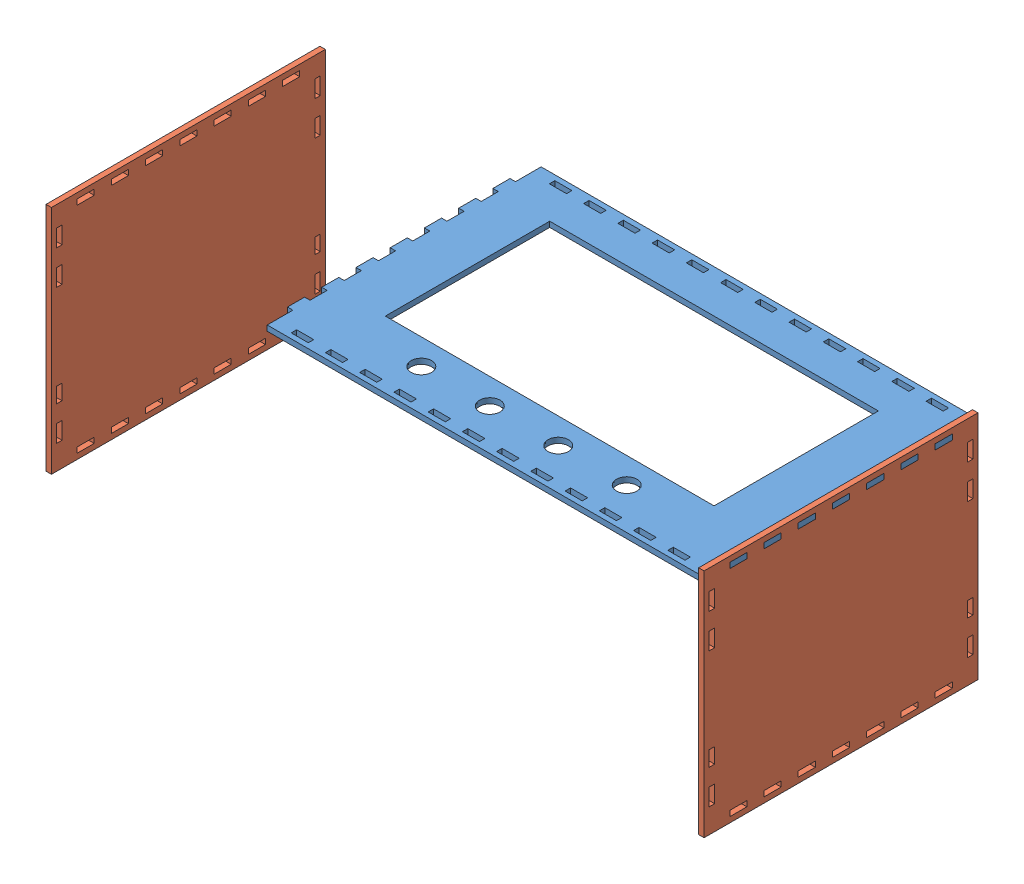
SolidWorks assembly Assem1, configuration Default. Lengths in mm.
Overall size (295.75 216.88 248.65).
3 component instances, 2 part files, 3 mates.
Components (placement in the parent):
- Top Plate-1: Top Plate [Default] at (-62.6363 155.6433 280.5323) size (258.35 3.17 160)
- Side Plate-1: Side Plate [Default] at (189.3637 26.9933 280.5323) x (0 0 -1) z (1 0 0) size (160 135 3.17)
- Side Plate-2: Side Plate [Default] at (-103.2072 108.87 369.179) x (0 0 -1) z (1 0 0) size (160 135 3.17)
Mates (geometry in assembly coordinates):
- Coincident1: coincident: plane of Top Plate-1 through (-62.6363 158.8183 265.5323) normal (0 0 1); line of Side Plate-1 through (192.5387 158.8183 265.5323) axis (0 -1 0)
- Coincident2: coincident: plane of Top Plate-1 through (-62.6363 158.8183 280.5323) normal (0 1 0); line of Side Plate-1 through (192.5387 158.8183 255.5323) axis (0 0 1)
- Coincident4: coincident aligned: plane of Top Plate-1 through (192.5387 158.8183 280.5323) normal (1 0 0); plane of Side Plate-1 through (192.5387 26.9933 280.5323) normal (1 0 0)
